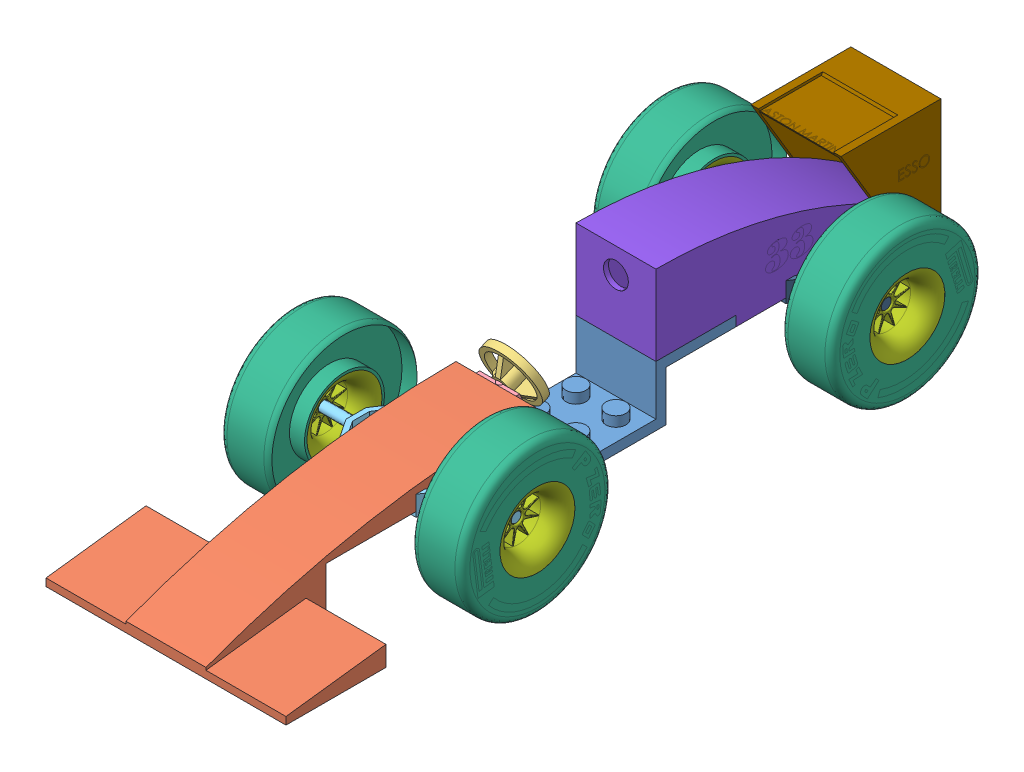
SolidWorks assembly Formule 1 auto lego, configuration Default. Lengths in mm.
Overall size (48.6 39.14 146).
22 component instances, 11 part files, 26 mates.
Components (placement in the parent):
- Bottom brick Formule 1-1: Bottom brick Formule 1 [Default] at (23.9887 35.2156 83.2357) size (16 14 64)
- Front brick-1: Front brick [Default] at (15.9887 40.3288 146.0881) size (48 14 66)
- Steering wheel assembly-1: Steering wheel assembly [Default] at (29.2962 28.3486 62.028) x (-1 0 0) z (0 0.400819 -0.916157) size (16 20.7 13.6)
  - Steering wheel-1: Steering wheel [Default] at (5.3075 7.6005 7.601) size (11.8 11.8 3.5)
  - Part7^Steering wheel assembly-1: Part7^Steering wheel assembly [Default] at origin (virtual)
  - Steering base-1: Steering base [Default] at (5.3075 -5.5928 4.9671) x (1 0 0) z (0 -0.400819 0.916157) size (16 15.65 8)
- Chassis-1: Chassis [Default] at (23.9887 32.2156 75.2357) size (40 4 16)
- Pirelli band +velg-1: Pirelli band +velg [Default] at (66.3557 46.5836 60.4675) x (0 -0.992143 -0.125105) z (-1 0 0) size (30 30 10)
  - pirelle band-1: pirelle band [groot] at (10.4233 16.1995 18.067) size (30 30 10)
  - Velg Pirelli-1: Velg Pirelli [Default] at (10.4233 16.1995 23.067) size (15 15 10)
- Pirelli band +velg-2: Pirelli band +velg [Default] at (-18.3783 19.5733 87.7527) x (0 -0.135143 -0.990826) z (1 0 0) size (30 30 10)
  - pirelle band-1: pirelle band [groot] at (10.4233 16.1995 18.067) size (30 30 10)
  - Velg Pirelli-1: Velg Pirelli [Default] at (10.4233 16.1995 23.067) size (15 15 10)
- achterkant formule 1-1: achterkant formule 1 [Default] at (23.9887 35.2156 35.2357) x (0 0 -1) z (1 0 0) size (56 18 16)
- spoiler formule 1-1: spoiler formule 1 [Default] at (23.9887 33.2156 -20.7643) x (0 0 1) z (-1 0 0) size (20 20 18)
- Chassis .-1: Chassis . [Default] at (23.9887 32.2156 1.2357) size (40 4 16)
- Pirelli band +velg-3: Pirelli band +velg [Default] at (-18.3783 37.7165 20.1781) x (0 -0.925294 -0.379249) z (1 0 0) size (30 30 10)
  - pirelle band-1: pirelle band [groot] at (10.4233 16.1995 18.067) size (30 30 10)
  - Velg Pirelli-1: Velg Pirelli [Default] at (10.4233 16.1995 23.067) size (15 15 10)
- Pirelli band +velg-4: Pirelli band +velg [Default] at (66.3557 19.5985 13.7822) x (0 0.95832 0.285696) z (-1 0 0) size (30 30 10)
  - pirelle band-1: pirelle band [groot] at (10.4233 16.1995 18.067) size (30 30 10)
  - Velg Pirelli-1: Velg Pirelli [Default] at (10.4233 16.1995 23.067) size (15 15 10)
Mates (geometry in assembly coordinates):
- Coincident1: coincident aligned: plane of Bottom brick Formule 1-1 through (31.9887 25.2156 59.2357) normal (0 0 -1); plane of Front brick-1 through (31.9887 39.2156 59.2357) normal (0 0 -1)
- Coincident2: coincident anti-aligned: plane of Bottom brick Formule 1-1 through (31.9887 35.2156 59.2357) normal (0 1 0); plane of Front brick-1 through (31.9887 35.2156 83.2357) normal (0 -1 0)
- Coincident3: coincident aligned: plane of Bottom brick Formule 1-1 through (31.9887 35.2156 83.2357) normal (1 0 0); plane of Front brick-1 through (31.9887 -148.2844 59.2357) normal (1 0 0)
- Coincident4: coincident anti-aligned: plane of Bottom brick Formule 1-1 through (31.9887 25.2156 35.2357) normal (0 1 0); plane of Steering wheel assembly-1/Steering base-1 through (23.9887 25.2156 55.2357) normal (0 -1 0)
- Coincident5: coincident anti-aligned: plane of Bottom brick Formule 1-1 through (31.9887 25.2156 59.2357) normal (0 0 -1); plane of Steering wheel assembly-1/Steering base-1 through (31.9887 28.2156 59.2357) normal (0 0 1)
- Coincident6: coincident aligned: plane of Bottom brick Formule 1-1 through (31.9887 35.2156 83.2357) normal (1 0 0); plane of Steering wheel assembly-1/Steering base-1 through (31.9887 28.2156 59.2357) normal (1 0 0)
- Coincident7: coincident anti-aligned: plane of Bottom brick Formule 1-1 through (31.9887 33.2156 83.2357) normal (0 -1 0); plane of Chassis-1 through (23.9887 33.2156 75.2357) normal (0 1 0)
- Coincident8: coincident aligned: plane of Bottom brick Formule 1-1 through (31.9887 35.2156 83.2357) normal (0 0 1); plane of Chassis-1 through (23.9887 33.2156 83.2357) normal (0 0 1)
- Coincident9: coincident anti-aligned: plane of Bottom brick Formule 1-1 through (31.9887 35.2156 83.2357) normal (1 0 0); plane of Chassis-1 through (31.9887 36.2156 81.4329) normal (-1 0 0)
- Concentric2: concentric aligned: cylinder of Chassis-1 through (43.9887 34.2156 75.2357) axis (-1 0 0) radius 1; cylinder of Pirelli band +velg-1/Velg Pirelli-1 through (44.2887 34.2156 75.2357) axis (-1 0 0) radius 1.05
- Coincident10: coincident aligned: plane of Chassis-1 through (43.9887 34.2156 75.2357) normal (1 0 0); circle of Pirelli band +velg-1/Velg Pirelli-1
- Concentric3: concentric aligned: cylinder of Chassis-1 through (3.9887 34.2156 75.2357) axis (1 0 0) radius 1; cylinder of Pirelli band +velg-2/Velg Pirelli-1 through (3.6887 34.2156 75.2357) axis (1 0 0) radius 1.05
- Coincident11: coincident aligned: plane of Chassis-1 through (3.9887 34.2156 75.2357) normal (-1 0 0); circle of Pirelli band +velg-2/Velg Pirelli-1
- Coincident12: coincident anti-aligned: plane of Bottom brick Formule 1-1 through (31.9887 35.2156 19.2357) normal (0 1 0); plane of achterkant formule 1-1 through (31.9887 35.2156 19.2357) normal (0 -1 0)
- Coincident13: coincident aligned: plane of Bottom brick Formule 1-1 through (31.9887 35.2156 35.2357) normal (0 0 1); plane of achterkant formule 1-1 through (31.9887 35.2156 35.2357) normal (0 0 1)
- Coincident14: coincident aligned: plane of Bottom brick Formule 1-1 through (15.9887 35.2156 83.2357) normal (-1 0 0); plane of achterkant formule 1-1 through (15.9887 -44.8956 35.2357) normal (-1 0 0)
- Coincident15: coincident aligned: plane of achterkant formule 1-1 through (31.9887 33.2156 -20.7643) normal (0 -1 0); plane of spoiler formule 1-1 through (14.9887 33.2156 -20.7643) normal (0 -1 0)
- Coincident16: coincident anti-aligned: plane of achterkant formule 1-1 through (15.9887 -44.8956 35.2357) normal (-1 0 0); plane of spoiler formule 1-1 through (15.9887 52.2156 17.2357) normal (1 0 0)
- Distance1: distance = 0 mm: plane of spoiler formule 1-1 through (14.9887 53.2156 -20.7643) normal (0 0 -1); line of achterkant formule 1-1 through (31.9887 33.2156 -20.7643) axis (-1 0 0)
- Coincident18: coincident: plane of achterkant formule 1-1 through (31.9887 33.2156 -20.7643) normal (0 -1 0); plane of Chassis .-1 through (23.9887 33.2156 1.2357) normal (0 1 0)
- Coincident19: coincident: plane of achterkant formule 1-1 through (15.9887 -44.8956 35.2357) normal (-1 0 0); plane of Chassis .-1 through (15.9887 36.2156 -6.7643) normal (1 0 0)
- Distance2: distance = 24 mm anti-aligned: plane of Chassis .-1 through (23.9887 33.2156 9.2357) normal (0 0 1); plane of Bottom brick Formule 1-1 through (31.9887 23.2156 33.2357) normal (0 0 -1)
- Concentric5: concentric: cylinder of Chassis .-1 through (3.9887 34.2156 1.2357) axis (1 0 0) radius 1.5; cylinder of Pirelli band +velg-3/Velg Pirelli-1 through (3.6887 34.2156 1.2357) axis (1 0 0) radius 1.05
- Coincident21: coincident aligned: plane of Chassis .-1 through (3.9887 34.2156 1.2357) normal (-1 0 0); circle of Pirelli band +velg-3/Velg Pirelli-1
- Concentric6: concentric: cylinder of Chassis .-1 through (43.9887 34.2156 1.2357) axis (-1 0 0) radius 1.5; cylinder of Pirelli band +velg-4/Velg Pirelli-1 through (44.2887 34.2156 1.2357) axis (-1 0 0) radius 1.05
- Coincident22: coincident aligned: plane of Chassis .-1 through (43.9887 34.2156 1.2357) normal (1 0 0); circle of Pirelli band +velg-4/Velg Pirelli-1
